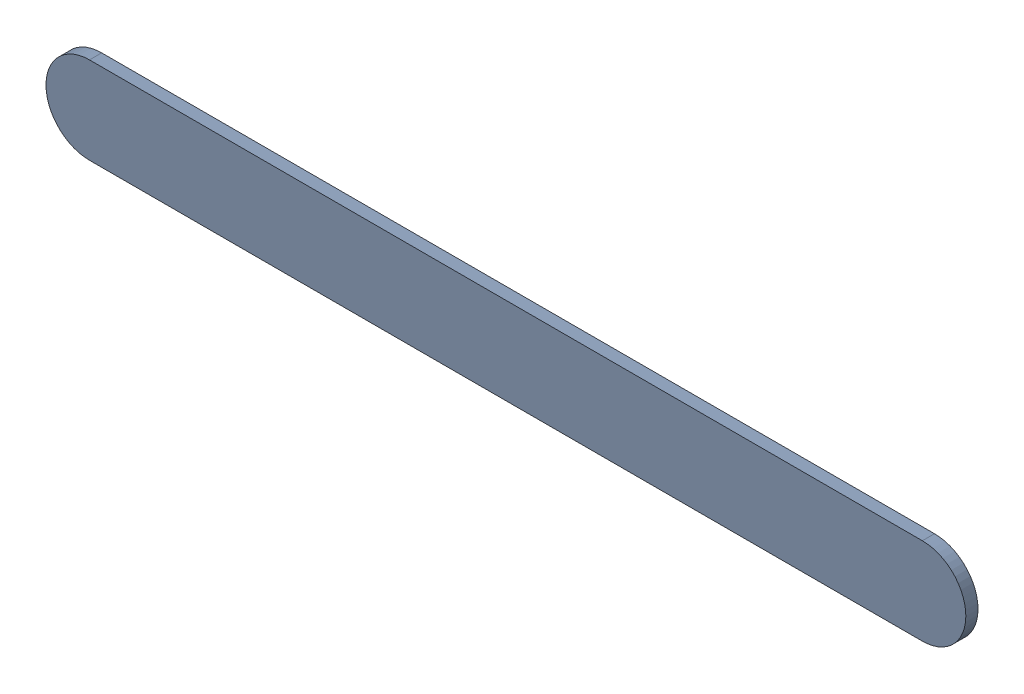
SolidWorks assembly Track (11.349mm,50.1mm)(13.781mm,50.1mm) on Top Layer, configuration Predeterminado. Lengths in mm.
Overall size (2.69 0.25 0.04).
2 component instances, 1 part files, 0 mates.
Components (placement in the parent):
- Track (11.349mm,50.1mm)(13.781mm,50.1mm) on Top Layer-1-1: Track (11.349mm,50.1mm)(13.781mm,50.1mm) on Top Layer-1 [Predeterminado] at (-68.317 -44.187 -0.0457) size (2.69 0.25 0.04)
  - Track (11.349mm,50.1mm)(13.781mm,50.1mm) on Top Layer-Part-1-1: Track (11.349mm,50.1mm)(13.781mm,50.1mm) on Top Layer-Part-1 [Predeterminado] at origin size (2.69 0.25 0.04)
